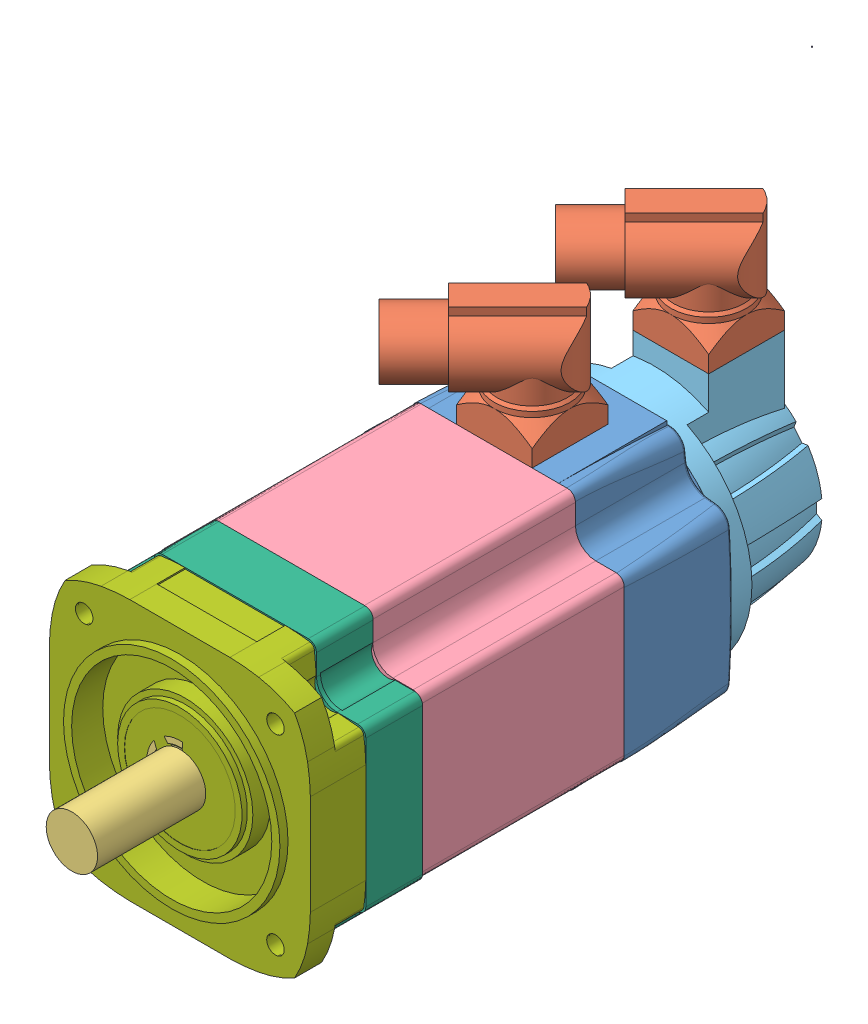
SolidWorks assembly dong co, configuration Default. Lengths in mm.
Overall size (359.59 418.15 320.58).
9 component instances, 8 part files, 20 mates.
Components (placement in the parent):
- 1-1: 1 [Default] at (25.4774 23.9529 173.2343) size (49.06 49.06 22.55)
- 2-1: 2 [Default] at (25.1933 -12.0644 196.74) size (25.74 22.45 25.74)
- 3-1: 3 [Default] at (25.7274 24.0246 98.1798) size (12.5 12.5 25)
- 4-1: 4 [Default] at (25.6024 24.1496 143.9558) size (48 48 37.5)
- 5-1: 5 [Default] at (25.2224 22.3533 194.9108) size (44 47.75 22.5)
- 6-1: 6 [Default] at (25.7274 24.0246 57.9533) x (-1 0 0) z (0 0 -1) size (48.25 48.25 10.5)
- 7-1: 7 [Default] at (25.7274 24.0246 109.7686) size (48.25 48.25 11.75)
- 8-1: 8 [Default] at (360.3442 417.4486 322.479) size (0.13 0.13 0.13)
- 2-2: 2 [Default] at (22.3183 -13.6894 226.49) size (25.74 22.45 25.74)
Mates (geometry in assembly coordinates):
- Coincident1: coincident anti-aligned: plane of 1-1 through (25.4774 24.0246 46.2058) normal (0 0 1); plane of 4-1 through (25.6024 24.1496 46.2058) normal (0 0 -1)
- Tangent1: tangent aligned: cylinder of 1-1 through (-205.3976 48.1496 46.2058) axis (0 -1 0) radius 255; plane of 4-1 through (49.6024 39.1496 46.2058) normal (1 0 0)
- Coincident2: coincident aligned: plane of 1-1 through (25.4774 48.1496 46.2058) normal (0 1 0); plane of 4-1 through (10.6024 48.1496 46.2058) normal (0 1 0)
- Coincident3: coincident anti-aligned: plane of 4-1 through (25.6024 24.1496 83.7058) normal (0 0 1); plane of 6-1 through (25.7274 24.0246 83.7058) normal (0 0 -1)
- Coincident4: coincident aligned: plane of 4-1 through (1.6024 9.1496 46.2058) normal (-1 0 0); plane of 6-1 through (1.6024 9.0246 83.7058) normal (-1 0 0)
- Coincident5: coincident aligned: plane of 4-1 through (10.6024 48.1496 46.2058) normal (0 1 0); plane of 6-1 through (10.7274 48.1496 83.7058) normal (0 1 0)
- Coincident6: coincident anti-aligned: plane of 6-1 through (25.7274 24.0246 94.2058) normal (0 0 1); plane of 7-1 through (25.7274 24.0246 94.2058) normal (0 0 -1)
- Coincident7: coincident aligned: plane of 6-1 through (1.6024 9.0246 83.7058) normal (-1 0 0); plane of 7-1 through (1.6024 33.2746 94.2058) normal (-1 0 0)
- Concentric1: concentric anti-aligned: cylinder of 6-1 through (43.4051 6.347 83.7058) axis (0 0 -1) radius 3; cylinder of 7-1 through (43.4051 6.347 94.2058) axis (0 0 1) radius 3
- Coincident8: coincident anti-aligned: plane of 1-1 through (25.4774 24.0246 24.4558) normal (0 0 -1); plane of 5-1 through (25.4774 24.0246 24.4558) normal (0 0 1)
- Coincident9: coincident aligned: circle of 1-1; circle of 5-1
- Parallel1: parallel aligned: plane of 4-1 through (10.6024 48.1496 46.2058) normal (0 1 0); plane of 5-1 through (25.4774 49.7746 24.4558) normal (0 1 0)
- Coincident11: coincident anti-aligned: plane of 2-1 through (25.4774 49.7746 104.4558) normal (0 -1 0); plane of 5-1 through (25.4774 49.7746 24.4558) normal (0 1 0)
- Coincident12: coincident aligned: plane of 2-1 through (35.4774 49.7746 2.4558) normal (0 0 -1); plane of 5-1 through (35.4774 24.0246 2.4558) normal (0 0 -1)
- Coincident13: coincident aligned: plane of 2-1 through (21.4774 49.7746 2.4558) normal (-1 0 0); plane of 5-1 through (21.4774 24.0246 2.4558) normal (-1 0 0)
- Concentric2: concentric aligned: cylinder of 3-1 through (25.7274 24.0246 125.6558) axis (0 0 -1) radius 4.75; cylinder of 7-1 through (25.7274 24.0246 103.6183) axis (0 0 -1) radius 12.5
- Coincident14: coincident aligned: plane of 3-1 through (25.7274 24.0246 104.4058) normal (0 0 1); plane of 7-1 through (25.7274 24.0246 104.4058) normal (0 0 1)
- Coincident15: coincident anti-aligned: plane of 1-1 through (25.4774 48.1496 46.2058) normal (0 1 0); plane of 2-2 through (22.6024 48.1496 134.2058) normal (0 -1 0)
- Coincident16: coincident aligned: line of 4-1 through (39.1024 48.1496 46.2058) axis (-1 0 0); line of 2-2 through (32.6024 48.1496 46.2058) axis (-1 0 0)
- Coincident17: coincident: point of 4-1; unknown of 2-2
